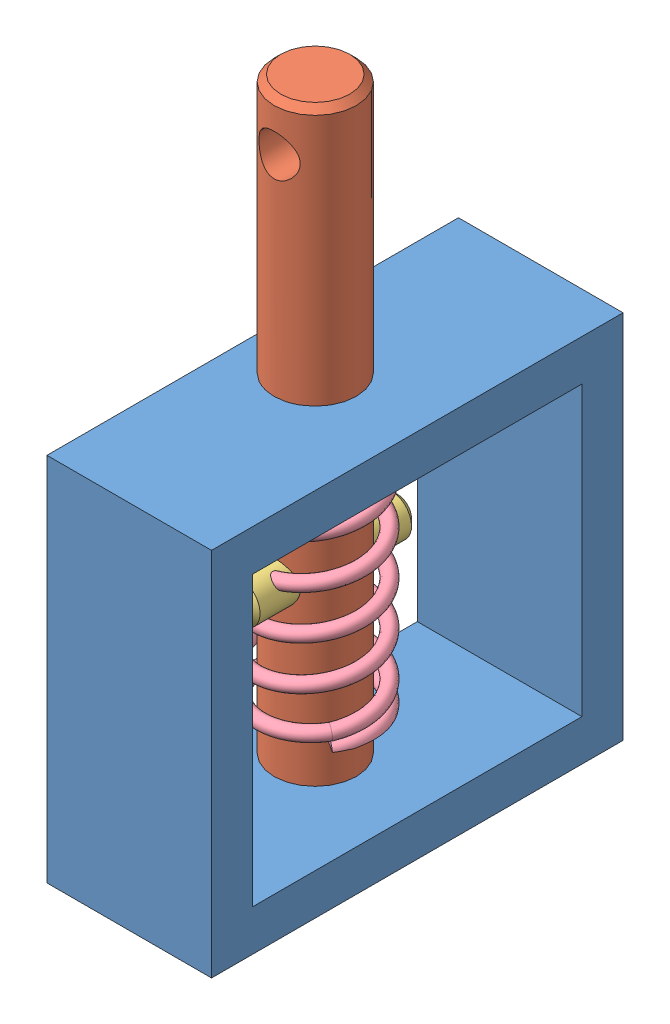
SolidWorks assembly Pin capture Assembly, configuration Default. Lengths in mm.
Overall size (14.32 50.8 31.75).
5 component instances, 5 part files, 11 mates.
Components (placement in the parent):
- Spring Capture-1: Spring Capture [Default] at (2.7623 3.5347 28.1383) size (12.7 28.57 31.75)
- Main Pin-1: Main Pin [Default] at (7.5883 1.2487 12.2633) x (-1 0 0) z (0 0 -1) size (6.35 50.8 6.35)
- Mini Pin-1: Mini Pin [Default] at (7.5883 19.7272 18.6133) x (0.998163 -0.060581 0) z (0 0 -1) size (3.17 3.17 12.7)
- Part2^Pin capture Assembly-1: Part2^Pin capture Assembly [Default] at (2.7623 32.1097 28.1383) x (1 0 0) z (0 1 0) (virtual)
- 9657K288_Compression Spring-2: 9657K288_Compression Spring [9657K288] at (7.5883 28.9347 12.2633) x (0.837169 0 0.546944) z (0 1 0) size (9.43 9.56 19.63)
Mates (geometry in assembly coordinates):
- Concentric1: concentric aligned: cylinder of Spring Capture-1 through (7.5883 32.1097 12.2633) axis (0 -1 0) radius 3.175; cylinder of Main Pin-1 through (7.5883 52.0487 12.2633) axis (0 -1 0) radius 3.175
- Distance1: distance = 6.35 mm anti-aligned: plane of Main Pin-1 through (7.5883 1.2487 12.2633) normal (0 0 -1); plane of Mini Pin-1 through (7.5883 19.7272 18.6133) normal (0 0 1)
- LimitDistance2: limit distance = 11.43 mm: cylinder of Mini Pin-1 through (7.5883 19.7272 5.9133) axis (0 0 1) radius 1.5875; plane of Spring Capture-1 through (2.7623 6.7097 28.1383) normal (0 1 0)
- Parallel1: parallel anti-aligned: plane of Spring Capture-1 through (2.7623 3.5347 28.1383) normal (1 0 0); plane of Main Pin-1 through (7.5883 1.2487 12.2633) normal (-1 0 0)
- Concentric3: concentric anti-aligned: cylinder of Main Pin-1 through (7.5883 19.7272 63.0633) axis (0 0 -1) radius 1.5875; cylinder of Mini Pin-1 through (7.5883 19.7272 5.9133) axis (0 0 1) radius 1.5875
- InPlace1: in place: plane of Spring Capture-1 through (2.7623 27.7917 28.1383) normal (0 1 0); plane of ? through (0 27.7917 0) normal (0 1 0); moOrthogonalPlaneRef_w of Spring Capture-1 through (2.7623 27.7917 28.1383) normal (0 1 0); plane of ? through (0 27.7917 0) normal (0 0 -1); plane of Spring Capture-1 through (2.7623 27.7917 28.1383) normal (0 1 0); plane of ? through (0 27.7917 0) normal (1 0 0); plane of Spring Capture-1 through (2.7623 32.1097 28.1383) normal (0 1 0); unknown of Part2^Pin capture Assembly-1
- Coincident1: coincident aligned: plane of Spring Capture-1 through (2.7623 32.1097 28.1383) normal (0 1 0); plane of Part2^Pin capture Assembly-1 through (2.7623 32.1097 28.1383) normal (0 1 0)
- Coincident2: coincident aligned: moOrthogonalPlaneRef_w of Spring Capture-1 through (2.7623 32.1097 28.1383) normal (0 0 -1); plane of Part2^Pin capture Assembly-1 through (2.7623 32.1097 28.1383) normal (0 0 -1)
- Coincident3: coincident anti-aligned: moOrthogonalPlaneRef_w of Spring Capture-1 through (2.7623 32.1097 28.1383) normal (-1 0 0); plane of Part2^Pin capture Assembly-1 through (2.7623 32.1097 28.1383) normal (1 0 0)
- Concentric4: concentric aligned: circle of Main Pin-1; line of 9657K288_Compression Spring-2 through (7.5883 8.8402 12.2633) axis (0 1 0)
- Coincident1: coincident anti-aligned: plane of Spring Capture-1 through (2.7623 28.9347 28.1383) normal (0 -1 0); plane of 9657K288_Compression Spring-2 through (7.5883 28.9347 12.2633) normal (0 1 0)
